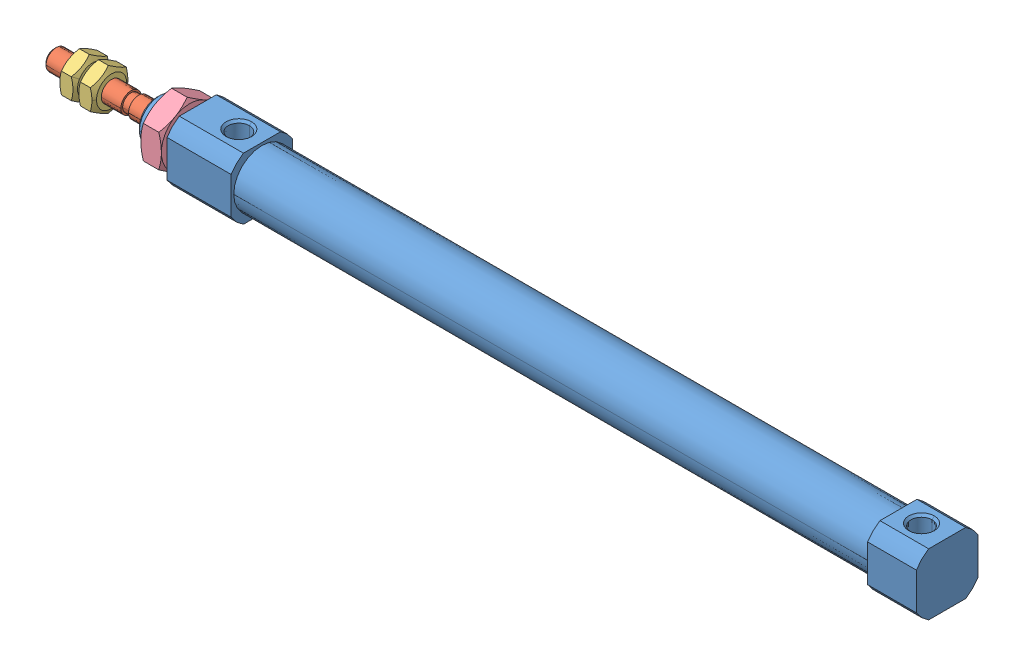
SolidWorks assembly CJ2B10_100Z_0_0_0_, configuration Default. Lengths in mm.
Overall size (174 12.72 14.18).
5 component instances, 4 part files, 0 mates.
Components (placement in the parent):
- _CJ2B10_100Z_0_0__BODY_2-1: _CJ2B10_100Z_0_0__BODY_2 [Default] at origin size (154 12 12)
- _CJ2B10_100Z_ROD_4-1: _CJ2B10_100Z_ROD_4 [Default] at (-28 0 0) size (145.5 10 10)
- _NTJ_010C_6-1: _NTJ_010C_6 [Default] at (-18.4 0 0) x (-1 0 0) z (0 0 1) size (3.2 8.09 9.3)
- _NTJ_010C_6-2: _NTJ_010C_6 [Default] at (-22.1 0 0) size (3.2 8.09 9.3)
- _SNJ_010C_9-1: _SNJ_010C_9 [Default] at (-3.6 0 0) size (4.02 12.72 14.18)
